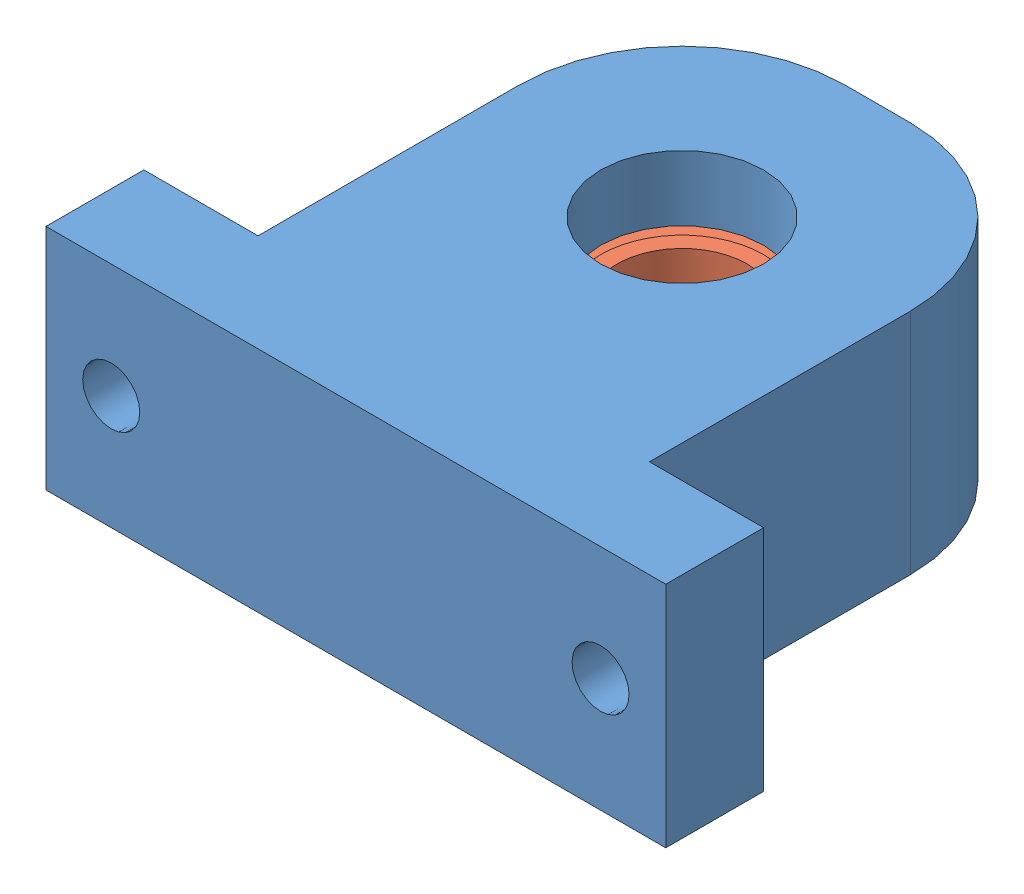
SolidWorks assembly Spindle_stabilizer, configuration Default. Lengths in mm.
Overall size (38 14 32).
2 component instances, 2 part files, 0 mates.
Components (placement in the parent):
- 688Z_V-slot_mount-1: 688Z_V-slot_mount [Default] at origin size (38 14 32)
- 688Z-1: 688Z [Default] at (0 0 -20) size (16 5 16)
